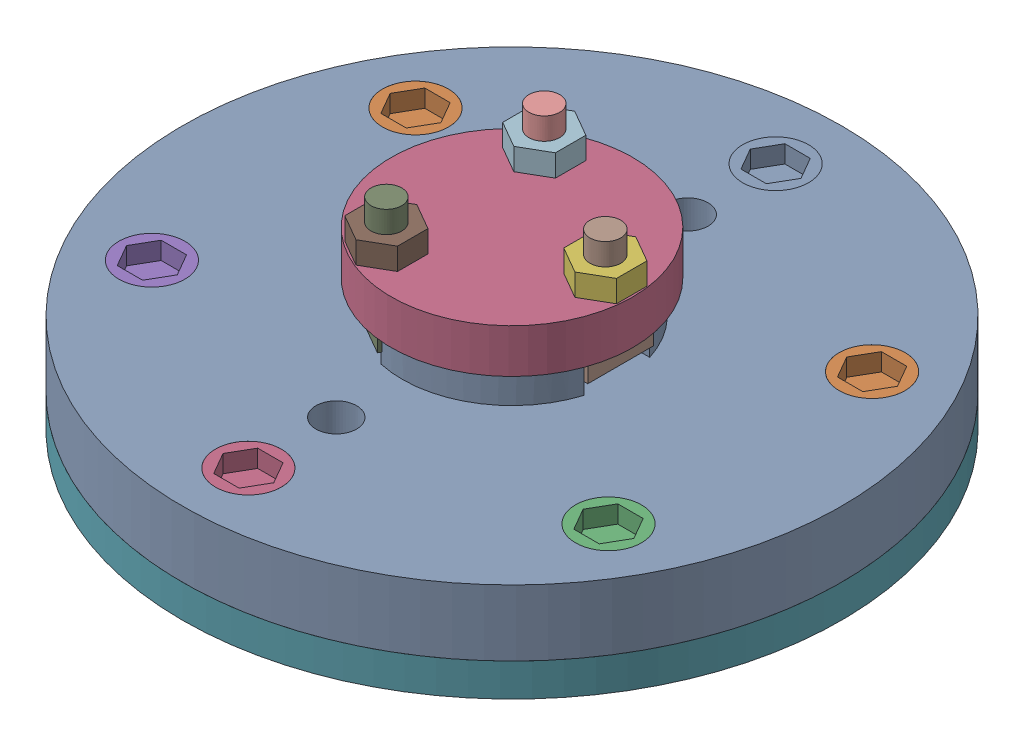
SolidWorks assembly Valve, configuration Default. Lengths in mm.
Overall size (300 157.25 300).
18 component instances, 8 part files, 21 mates.
Components (placement in the parent):
- Disc-1: Disc [Default] at origin size (300 130 300)
- Bolt-1: Bolt [Default] at (-103.923 55 -60) x (0.5 0 -0.866025) z (0.866025 0 0.5) size (30 45 30)
- Bush-1: Bush [Default] at (0 10 0) size (100 25 100)
- Cover-1: Cover [Default] at (0 115 0) x (0.860012 0 -0.510274) z (0.510274 0 0.860012) size (110 20 110)
- Key-1: Key [Default] at (33 17.75 0) x (0 1 0) z (0 0 1) size (40 7.5 15.5)
- Nut-1: Nut [Default] at (41.997 145 -0.5) x (0.866025 0 -0.5) z (-0.5 0 -0.866025) size (27.71 10 24)
- Plate-1: Plate [Default] at (0 55 0) size (300 15 300)
- T_Bolt-4: T_Bolt [Default] at (41.997 105 -0.5) x (-1 0 0) z (0 0 -1) size (14 50 30)
- T_Bolt-5: T_Bolt [Default] at (-20.5655 105 36.6205) x (0.5 0 -0.866025) z (0.866025 0 0.5) size (14 50 30)
- T_Bolt-6: T_Bolt [Default] at (-21.4315 105 -36.1205) x (0.5 0 0.866025) z (-0.866025 0 0.5) size (14 50 30)
- Nut-2: Nut [Default] at (-20.5655 145 36.6205) x (0 0 1) z (1 0 0) size (27.71 10 24)
- Nut-3: Nut [Default] at (-21.4315 145 -36.1205) x (-0.866025 0 -0.5) z (-0.5 0 0.866025) size (27.71 10 24)
- Bolt-2: Bolt [Default] at (0 55 -120) size (30 45 30)
- Bolt-3: Bolt [Default] at (103.923 55 -60) x (0.5 0 0.866025) z (-0.866025 0 0.5) size (30 45 30)
- Bolt-4: Bolt [Default] at (103.923 55 60) x (-0.5 0 0.866025) z (-0.866025 0 -0.5) size (30 45 30)
- Bolt-5: Bolt [Default] at (0 55 120) x (-1 0 0) z (0 0 -1) size (30 45 30)
- Bolt-6: Bolt [Default] at (-103.923 55 60) x (-0.5 0 -0.866025) z (0.866025 0 -0.5) size (30 45 30)
- Key-2: Key [Default] at (-33 17.75 0) x (0 1 0) z (0 0 -1) size (40 7.5 15.5)
Mates (geometry in assembly coordinates):
- Tangent1: tangent anti-aligned: plane of Disc-1 through (79.392 130 -7.5) normal (0 0 1); cylinder of T_Bolt-4 through (41.997 155 -0.5) axis (0 -1 0) radius 7
- Coincident3: coincident anti-aligned: circle of Disc-1; plane of T_Bolt-4 through (41.997 115 -0.5) normal (0 1 0)
- Concentric1: concentric aligned: cylinder of Disc-1 through (0 0 0) axis (0 -1 0) radius 50; cylinder of Cover-1 through (0 135 0) axis (0 -1 0) radius 55
- Coincident5: coincident anti-aligned: plane of Disc-1 through (-50 130 0) normal (0 1 0); plane of Cover-1 through (0 130 0) normal (0 -1 0)
- Concentric3: concentric aligned: cylinder of Cover-1 through (41.997 135 -0.5) axis (0 -1 0) radius 7; cylinder of T_Bolt-4 through (41.997 155 -0.5) axis (0 -1 0) radius 7
- Parallel1: parallel aligned: plane of Disc-1 through (35 115 15) normal (1 0 0); plane of T_Bolt-4 through (48.997 115 14.5) normal (1 0 0)
- Concentric4: concentric anti-aligned: cylinder of Nut-1 through (41.997 135 -0.5) axis (0 1 0) radius 7; cylinder of T_Bolt-4 through (41.997 155 -0.5) axis (0 -1 0) radius 7
- Coincident7: coincident anti-aligned: plane of Cover-1 through (0 135 0) normal (0 1 0); plane of Nut-1 through (41.997 135 -0.5) normal (0 -1 0)
- Parallel2: parallel aligned: plane of Nut-1 through (53.997 135 -7.4282) normal (1 0 0); plane of T_Bolt-4 through (48.997 115 14.5) normal (1 0 0)
- Concentric5: concentric aligned: cylinder of Disc-1 through (0 0 0) axis (0 -1 0) radius 150; cylinder of Plate-1 through (0 70 0) axis (0 -1 0) radius 65
- Concentric6: concentric anti-aligned: cylinder of Disc-1 through (0 100 120) axis (0 1 0) radius 10; cylinder of Plate-1 through (0 70 120) axis (0 -1 0) radius 10
- Coincident8: coincident anti-aligned: circle of Disc-1; plane of Plate-1 through (0 70 0) normal (0 1 0)
- Concentric7: concentric anti-aligned: cylinder of Disc-1 through (-103.923 100 -60) axis (0 1 0) radius 10; cylinder of Bolt-1 through (-103.923 90 -60) axis (0 -1 0) radius 10
- Coincident9: coincident aligned: circle of Disc-1; circle of Bolt-1
- Parallel3: parallel aligned: plane of Bolt-1 through (-98.1495 100 -70) normal (0 0 1)
- Concentric8: concentric aligned: cylinder of Disc-1 through (0 0 0) axis (0 -1 0) radius 15; cylinder of Bush-1 through (0 25 0) axis (0 -1 0) radius 30
- Parallel4: parallel anti-aligned: plane of Disc-1 through (25 30 0) normal (1 0 0); plane of Bush-1 through (33 25 0) normal (-1 0 0)
- Distance1: distance = 10 mm aligned: plane of Disc-1 through (-15 0 0) normal (0 -1 0); plane of Bush-1 through (0 10 0) normal (0 -1 0)
- Coincident11: coincident anti-aligned: plane of Bush-1 through (33 25 0) normal (-1 0 0); plane of Key-1 through (33 5.5 0) normal (1 0 0)
- Concentric9: concentric anti-aligned: cylinder of Disc-1 through (150 30 0) axis (-1 0 0) radius 8; cylinder of Key-1 through (25.5 30 0) axis (1 0 0) radius 7.75
- Parallel5: parallel aligned: plane of Disc-1 through (0 30 -8) normal (0 0 1); plane of Key-1 through (25.5 5.5 7.75) normal (0 0 1)
